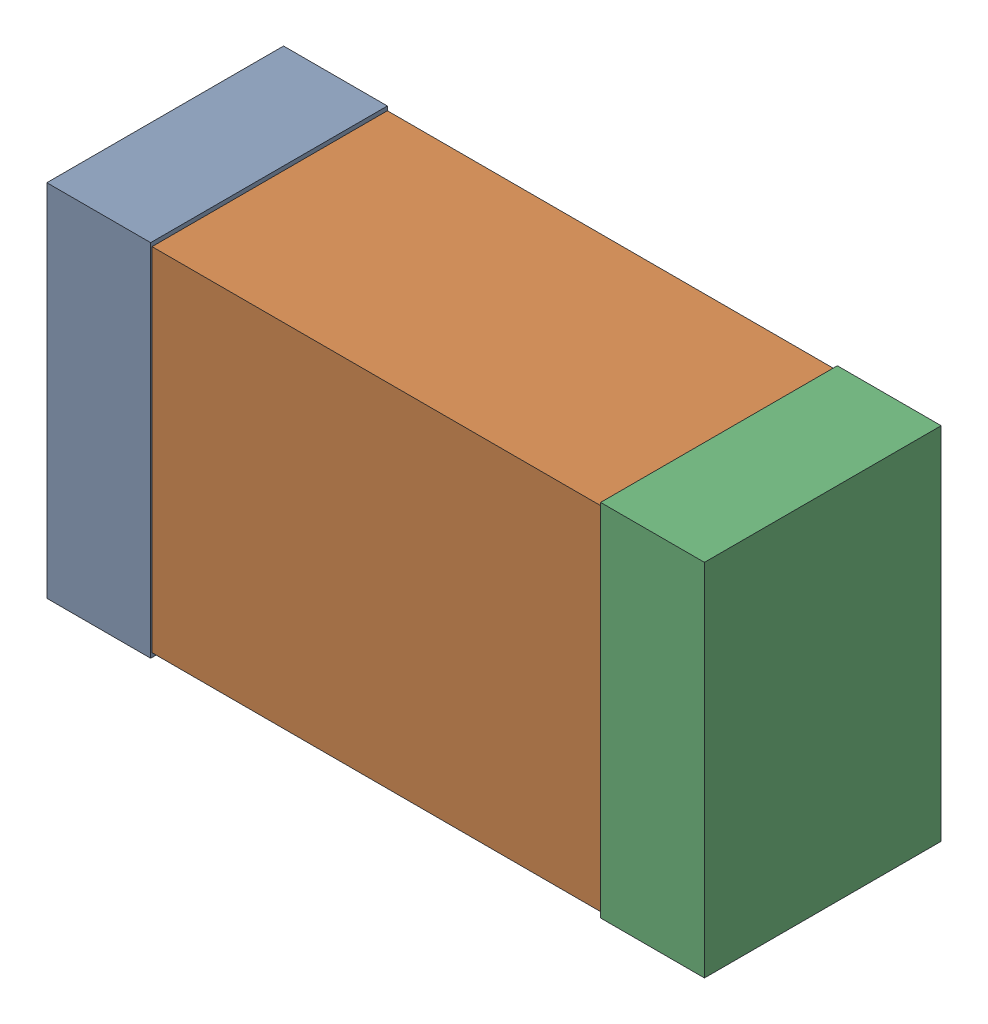
SolidWorks assembly R3_Motor_8Kanaloa_v2.0.0_Motor, configuration Default. Lengths in mm.
Overall size (2.38 1.3 0.85).
6 component instances, 2 part files, 0 mates.
Components (placement in the parent):
- 352877648-1: 352877648 [Default] at (127.012 147.701 0) size (0.38 1.3 0.85)
  - Extruded_14-1: Extruded_14 [Default] at origin size (0.38 1.3 0.85)
- 352877392-1: 352877392 [Default] at (128.012 147.701 0) size (2.2 1.27 0.85)
  - Extruded_15-1: Extruded_15 [Default] at origin size (2.2 1.27 0.85)
- 352877648-2: 352877648 [Default] at (129.012 147.701 0) size (0.38 1.3 0.85)
  - Extruded_14-1: Extruded_14 [Default] at origin size (0.38 1.3 0.85)
